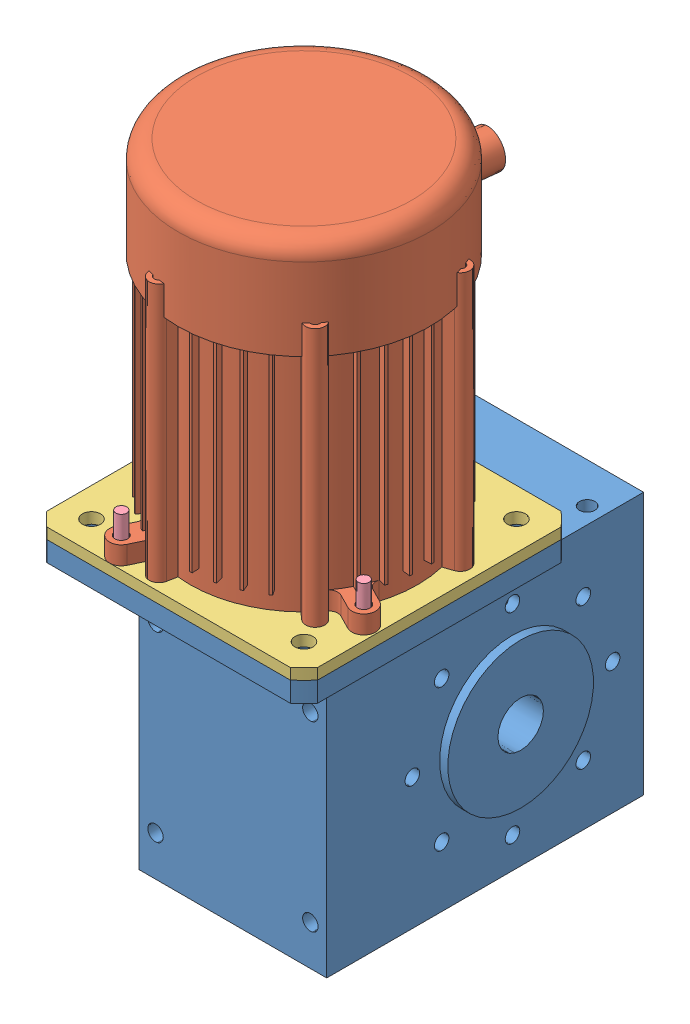
SolidWorks assembly Сборка двигателя и редуктора, configuration 00. Lengths in mm.
Overall size (193.31 354 223.77).
8 component instances, 4 part files, 19 mates.
Components (placement in the parent):
- Редуктор NRMV 063-1: Редуктор NRMV 063 [По умолчанию] at (0 0 -87) x (1 0 0) z (0 -1 0) size (148.67 209.34 167)
- Мотор BDLC (1.5квт) GWZ-1: Мотор BDLC (1.5квт) GWZ [По умолчанию] at (0 101 48) x (0 -1 0) z (0.947153 0 -0.320781) size (247 171.55 146)
- ТП.017.03.01.02 - Кронштейн двигателя (Ст3)-1: ТП.017.03.01.02 - Кронштейн двигателя (Ст3) [6мм - Правая] at (0 95 48) x (1 0 0) z (0 -1 0) size (148.67 148.67 6)
- Винт с потайной головкой 6х15мм-1: Винт с потайной головкой 6х15мм [6х25мм] at (66.9966 98 82.1543) x (0 1 0) z (0.074042 0 0.997255) size (28 11 11)
- Винт с потайной головкой 6х15мм-2: Винт с потайной головкой 6х15мм [6х15мм] at (42.6219 98 33.5649) x (0 1 0) z (0.260653 0 0.965433) size (18 11 11)
- Винт с потайной головкой 6х15мм-3: Винт с потайной головкой 6х15мм [6х15мм] at (-14.4351 98 5.3781) x (0 1 0) z (0.462646 0 0.886543) size (18 11 11)
- Винт с потайной головкой 6х15мм-4: Винт с потайной головкой 6х15мм [6х15мм] at (-42.6219 98 62.4351) x (0 1 0) z (0.657587 0 0.753379) size (18 11 11)
- Винт с потайной головкой 6х15мм-5: Винт с потайной головкой 6х15мм [6х25мм] at (-32.4545 98 115.8363) x (0 1 0) z (0.818466 0 0.574556) size (28 11 11)
Mates (geometry in assembly coordinates):
- Симметричный1: symmetric: plane of Редуктор NRMV 063-1 through (0 0 87) normal (0 0 1); plane of Редуктор NRMV 063-1 through (0 0 -87) normal (0 0 -1); plane of assembly
- Симметричный2: symmetric: plane of Редуктор NRMV 063-1 through (-51.5 -72 87) normal (0 -1 0); plane of Редуктор NRMV 063-1 through (-51.5 72 87) normal (0 1 0); plane of assembly
- Симметричный5: symmetric: plane of Редуктор NRMV 063-1 through (51.5 72 87) normal (1 0 0); plane of Редуктор NRMV 063-1 through (-51.5 72 87) normal (-1 0 0); plane of assembly
- Концентричный1: concentric: cylinder of Редуктор NRMV 063-1 through (0 37 48) axis (0 1 0) radius 11; cylinder of Мотор BDLC (1.5квт) GWZ-1 through (0 1101 48) axis (0 1 0) radius 12.5
- Расстояние1: distance = 6 mm: plane of Мотор BDLC (1.5квт) GWZ-1 through (-20.0488 101 -11.1971) normal (0 -1 0); plane of Редуктор NRMV 063-1 through (0 95 148) normal (0 1 0)
- Касательность1: tangent: plane of Редуктор NRMV 063-1 through (-74.3363 78 122.3363) normal (0 0 1); cylinder of Мотор BDLC (1.5квт) GWZ-1 through (-32.4545 139.73 115.8363) axis (0 -1 0) radius 6.5
- Совпадение3: coincident: plane of Редуктор NRMV 063-1 through (0 95 148) normal (0 1 0); plane of ТП.017.03.01.02 - Кронштейн двигателя (Ст3)-1 through (0 95 48) normal (0 -1 0)
- Симметричный6: symmetric: plane of Редуктор NRMV 063-1 through (-74.3363 78 122.3363) normal (0 0 1); plane of Редуктор NRMV 063-1 through (-74.3363 78 -26.3363) normal (0 0 -1); plane of ТП.017.03.01.02 - Кронштейн двигателя (Ст3)-1 through (0 95 48) normal (0 0 1)
- Симметричный7: symmetric: plane of Редуктор NRMV 063-1 through (-74.3363 78 122.3363) normal (-1 0 0); plane of Редуктор NRMV 063-1 through (74.3363 78 122.3363) normal (1 0 0); plane of ТП.017.03.01.02 - Кронштейн двигателя (Ст3)-1 through (0 95 48) normal (1 0 0)
- Концентричный2: concentric: cylinder of ТП.017.03.01.02 - Кронштейн двигателя (Ст3)-1 through (66.9966 101 82.1543) axis (0 -1 0) radius 3.5; cylinder of Винт с потайной головкой 6х15мм-1 through (66.9966 -902 82.1543) axis (0 -1 0) radius 3
- Совпадение4: coincident: plane of ТП.017.03.01.02 - Кронштейн двигателя (Ст3)-1 through (0 95 48) normal (0 -1 0); plane of Винт с потайной головкой 6х15мм-1 through (66.9966 95 82.1543) normal (0 -1 0)
- Концентричный3: concentric: cylinder of Мотор BDLC (1.5квт) GWZ-1 through (42.6219 101 33.5649) axis (0 -1 0) radius 2.5; cylinder of Винт с потайной головкой 6х15мм-2 through (42.6219 -902 33.5649) axis (0 -1 0) radius 3
- Совпадение5: coincident: plane of ТП.017.03.01.02 - Кронштейн двигателя (Ст3)-1 through (0 95 48) normal (0 -1 0); plane of Винт с потайной головкой 6х15мм-2 through (42.6219 95 33.5649) normal (0 -1 0)
- Совпадение6: coincident: plane of ТП.017.03.01.02 - Кронштейн двигателя (Ст3)-1 through (0 95 48) normal (0 -1 0); plane of Винт с потайной головкой 6х15мм-3 through (-14.4351 95 5.3781) normal (0 -1 0)
- Концентричный4: concentric: cylinder of Мотор BDLC (1.5квт) GWZ-1 through (-14.4351 101 5.3781) axis (0 -1 0) radius 2.5; cylinder of Винт с потайной головкой 6х15мм-3 through (-14.4351 -902 5.3781) axis (0 -1 0) radius 3
- Совпадение7: coincident: plane of ТП.017.03.01.02 - Кронштейн двигателя (Ст3)-1 through (0 95 48) normal (0 -1 0); plane of Винт с потайной головкой 6х15мм-4 through (-42.6219 95 62.4351) normal (0 -1 0)
- Концентричный5: concentric: cylinder of Мотор BDLC (1.5квт) GWZ-1 through (-42.6219 101 62.4351) axis (0 -1 0) radius 2.5; cylinder of Винт с потайной головкой 6х15мм-4 through (-42.6219 -902 62.4351) axis (0 -1 0) radius 3
- Совпадение8: coincident: plane of ТП.017.03.01.02 - Кронштейн двигателя (Ст3)-1 through (0 95 48) normal (0 -1 0); plane of Винт с потайной головкой 6х15мм-5 through (-32.4545 95 115.8363) normal (0 -1 0)
- Концентричный6: concentric: cylinder of Мотор BDLC (1.5квт) GWZ-1 through (-32.4545 139.73 115.8363) axis (0 -1 0) radius 3.5; cylinder of Винт с потайной головкой 6х15мм-5 through (-32.4545 -902 115.8363) axis (0 -1 0) radius 3
